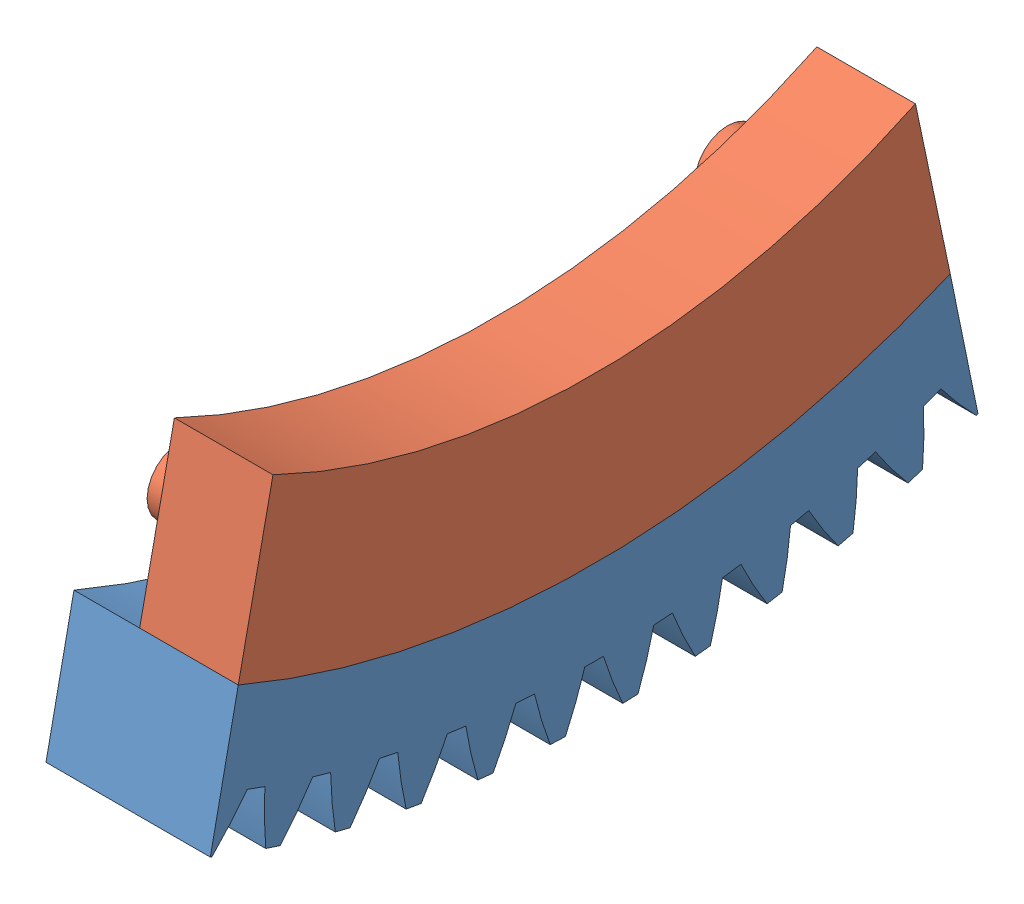
SolidWorks assembly Assem2, configuration Default. Lengths in mm.
Overall size (10 22.7 46.72).
2 component instances, 2 part files, 2 mates.
Components (placement in the parent):
- Metric - Spur gear 1.375M 90T 20PA 10FW ---S90O75H50L110N-1: Metric - Spur gear 1.375M 90T 20PA 10FW ---S90O75H50L110N [Metric - Spur gear 1.375M 90T 20PA 10FW ---S90O75H50L110N] at (-1.8854 10.4513 -8.744) size (10 126.45 126.5)
- 3d_extend-1: 3d_extend [Default] at (8.1146 10.4513 -8.744) x (0 0 1) z (-1 0 0) size (43.33 14.47 8.54)
Mates (geometry in assembly coordinates):
- Coincident1: coincident: circle of Metric - Spur gear 1.375M 90T 20PA 10FW ---S90O75H50L110N-1; circle of 3d_extend-1
- Coincident3: coincident: point of Metric - Spur gear 1.375M 90T 20PA 10FW ---S90O75H50L110N-1; point of 3d_extend-1
